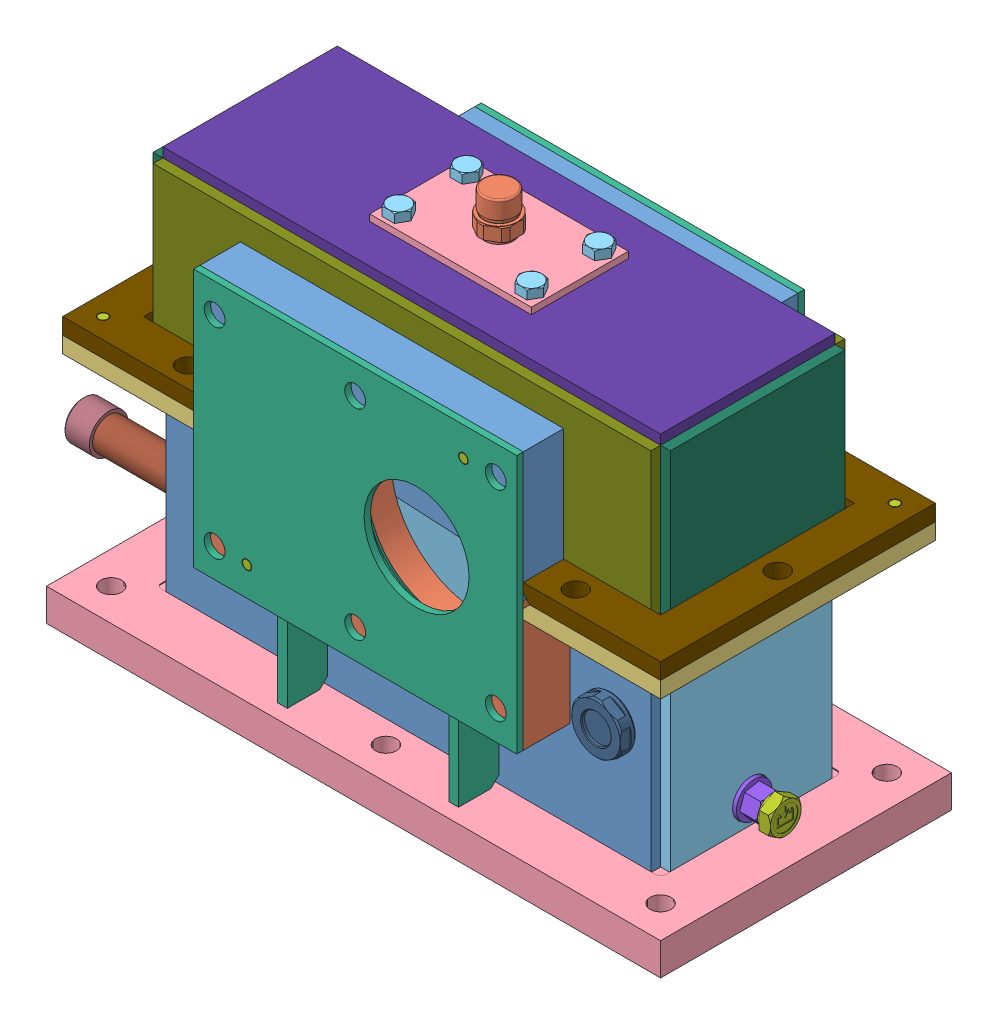
SolidWorks assembly kuciste_bez_poklopca, configuration Default. Lengths in mm.
Overall size (410 284 180).
61 component instances, 25 part files, 19 mates.
Components (placement in the parent):
- DONJE_KUCISTE-1: DONJE_KUCISTE [zajedno obrađeno] at (117.7992 130.0596 336.2434) size (410 154.5 180)
  - glavni_lim-1: glavni_lim [rupa za staklo] at (0 84.5 50) x (1 0 0) z (0 -1 0) size (300 6 130)
  - kockavratila-1: kockavratila [probusena_s_rupama_prednja] at (0 114.5 50) x (1 0 0) z (0 -1 0) size (200 35 80)
  - prirubnica_donja-1: prirubnica_donja [urezana_s_rupama] at (-100 144.5 0) size (85 10 170)
  - temeljna_ploca-1: temeljna_ploca [Default] at origin size (380 20 180)
  - bocni_lim-2: bocni_lim [cijevni registar] at (-150 84.5 0) x (0 0 -1) z (0 1 0) size (100 6 130)
  - glavni_lim-2: glavni_lim [Default] at (0 84.5 -56) x (1 0 0) z (0 -1 0) size (300 6 130)
  - kockavratila-2: kockavratila [probusena_s_rupama_zadnja] at (0 114.5 -50) x (-1 0 0) z (0 -1 0) size (200 35 80)
  - prirubnica_donja-2: prirubnica_donja [urezana_s_rupama] at (100 144.5 0) x (-1 0 0) z (0 0 -1) size (85 10 170)
  - bocni_lim-3: bocni_lim [irezan_ispust] at (156 84.5 0) x (0 0 1) z (0 -1 0) size (100 6 130)
  - rebro-1: rebro [Default] at (-50 47.25 68.5) x (0 -1 0) z (0 0 -1) size (54.5 6 25)
  - rebro-2: rebro [Default] at (50 47.25 68.5) x (0 1 0) z (0 0 -1) size (54.5 6 25)
  - rebro-3: rebro [Default] at (56 47.25 -68.5) x (0 1 0) z (0 0 1) size (54.5 6 25)
  - rebro-4: rebro [Default] at (-50 47.25 -68.5) x (0 1 0) z (0 0 1) size (54.5 6 25)
  - Oil fill plugs TCD.10x1.5-1: Oil fill plugs TCD.10x1.5 [Default] at (161.5 34.5 0) size (16 24.13 19)
  - Hexagon nut DIN 6331-M10-1: Hexagon nut DIN 6331-M10 [Default] at (154 34.5 0) x (0 -0.652064 0.758164) z (0 0.758164 0.652064) size (22 15 22)
  - Brass nut GH.M26x1.5-NK-1: Brass nut GH.M26x1.5-NK [Default] at (125 88.5 50) x (0 0 1) z (-0.706547 -0.707666 0) size (3.5 33 30)
  - Oil level sight glass GN 743-18-M26x1_5-A-1: Oil level sight glass GN 743-18-M26x1_5-A [Default] at (125 88.5 48) x (1 0 0) z (0 -1 0) size (32 17 32)
  - Prirubnica_c.reg._sklop-1: Prirubnica_c.reg._sklop [Default] at (-142.8722 78.3632 -24.5463) x (0 0.999301 0.037387) z (0 -0.037387 0.999301) size (33.22 66 33.22)
    - prirubnica_cijevnog_registra-1: prirubnica_cijevnog_registra [Default] at (-7.5365 11.1278 62.3717) size (20 50 20)
    - Gasket DIN 7603-AL-8-11_5-A(semering registra)-1: Gasket DIN 7603-AL-8-11_5-A(semering registra) [Default] at (-7.5365 26.6278 62.3717) x (0 -1 0) z (0.887885 0 0.460066) size (1 11.4 11.4)
    - Gasket DIN 7603-AL-8-11_5-A(semering registra)-2: Gasket DIN 7603-AL-8-11_5-A(semering registra) [Default] at (-7.5365 28.6278 62.3717) x (0 -1 0) z (-0.546944 0 0.837169) size (1 11.4 11.4)
    - Gasket DIN 7603-AL-8-11_5-A(semering registra)-3: Gasket DIN 7603-AL-8-11_5-A(semering registra) [Default] at (-7.5365 29.6278 62.3717) x (0 1 0) z (-0.564882 0 -0.825172) size (1 11.4 11.4)
    - Gasket DIN 7603-AL-8-11_5-A(semering registra)-4: Gasket DIN 7603-AL-8-11_5-A(semering registra) [Default] at (-7.5365 30.6278 62.3717) x (0 1 0) z (-0.564882 0 -0.825172) size (1 11.4 11.4)
    - Gasket DIN 7603-AL-8-11_5-A(semering registra)-5: Gasket DIN 7603-AL-8-11_5-A(semering registra) [Default] at (-7.5365 27.6278 62.3717) x (0 -1 0) z (-0.546944 0 0.837169) size (1 11.4 11.4)
    - M16x30-1: M16x30 [Default] at (-7.5365 77.1278 62.3717) x (0 -1 0) z (-0.546944 0 0.837169) size (46 24 24)
  - Prirubnica_c.reg._sklop-2: Prirubnica_c.reg._sklop [Default] at (-142.8722 84.718 -98.196) x (0 0.990097 0.140386) z (0 -0.140386 0.990097) size (33.22 66 33.22)
    - prirubnica_cijevnog_registra-1: prirubnica_cijevnog_registra [Default] at (-7.5365 11.1278 62.3717) size (20 50 20)
    - Gasket DIN 7603-AL-8-11_5-A(semering registra)-1: Gasket DIN 7603-AL-8-11_5-A(semering registra) [Default] at (-7.5365 26.6278 62.3717) x (0 -1 0) z (0.887885 0 0.460066) size (1 11.4 11.4)
    - Gasket DIN 7603-AL-8-11_5-A(semering registra)-2: Gasket DIN 7603-AL-8-11_5-A(semering registra) [Default] at (-7.5365 28.6278 62.3717) x (0 -1 0) z (-0.546944 0 0.837169) size (1 11.4 11.4)
    - Gasket DIN 7603-AL-8-11_5-A(semering registra)-3: Gasket DIN 7603-AL-8-11_5-A(semering registra) [Default] at (-7.5365 29.6278 62.3717) x (0 1 0) z (-0.564882 0 -0.825172) size (1 11.4 11.4)
    - Gasket DIN 7603-AL-8-11_5-A(semering registra)-4: Gasket DIN 7603-AL-8-11_5-A(semering registra) [Default] at (-7.5365 30.6278 62.3717) x (0 1 0) z (-0.564882 0 -0.825172) size (1 11.4 11.4)
    - Gasket DIN 7603-AL-8-11_5-A(semering registra)-5: Gasket DIN 7603-AL-8-11_5-A(semering registra) [Default] at (-7.5365 27.6278 62.3717) x (0 -1 0) z (-0.546944 0 0.837169) size (1 11.4 11.4)
    - M16x30-1: M16x30 [Default] at (-7.5365 77.1278 62.3717) x (0 -1 0) z (-0.546944 0 0.837169) size (46 24 24)
  - unutarnji lim-1: unutarnji lim [Default] at (-1.7035 28.2254 0) x (0.99863 -0.052336 0) z (0 0 -1) size (296.96 17.98 100)
- GORNJE KUČIŠTE-1: GORNJE KUČIŠTE [zajednicki obrađena] at (84.6226 294.5596 336.2434) x (-1 0 0) z (0 0 1) size (370 129.5 170)
  - gornji bočni lim veći-1: gornji bočni lim veći [Default] at (-187.1766 -40 0) x (0 1 0) z (0 0 1) size (90 6 108)
  - gornji glavni lim-1: gornji glavni lim [Default] at (27.434 -40 -60) x (-1 0 0) z (0 1 0) size (308 6 90)
  - gornji_gornji lim ravni-1: gornji_gornji lim ravni [Default] at (-33.1766 -91 0) size (308 6 108)
  - prirubnica_gornja-1: prirubnica_gornja [prirubnica s rupama ] at origin size (85 10 170)
  - gornji bočni lim veći-2: gornji bočni lim veći [Default] at (126.8234 -40 0) x (0 1 0) z (0 0 1) size (90 6 108)
  - gornji glavni lim-2: gornji glavni lim [Default] at (-93.7872 -40 60) x (1 0 0) z (0 1 0) size (308 6 90)
  - prirubnica_gornja-2: prirubnica_gornja [prirubnica s rupama ] at (-66.3532 0 0) x (-1 0 0) z (0 0 -1) size (85 10 170)
  - gornja kocka vratila-1: gornja kocka vratila [prednja_probusena_s_rupama] at (-33.1766 -30 50) x (-1 0 0) z (0 1 0) size (200 35 80)
  - gornja kocka vratila-2: gornja kocka vratila [zadnja_probusena_s_rupama] at (-33.1766 -30 -50) x (1 0 0) z (0 1 0) size (200 35 80)
  - poklopac sa odzračnikom-1: poklopac sa odzračnikom [Default] at (-34.3484 -81.4985 -29.5408) x (-1 0 0) z (0 0 1) size (100 33 60)
    - Breather valve GN 881-M12x1_5-200-MS-M-1: Breather valve GN 881-M12x1_5-200-MS-M [Default] at (-1.1718 13.5015 29.5408) size (23 33 23.5)
    - Mounting nut GN 7430-M12x1_5-MS-1: Mounting nut GN 7430-M12x1_5-MS [Default] at (-1.1718 6.5015 29.5408) x (1 0 0) z (0 -1 0) size (16 17.5 3)
    - poklopac-1: poklopac [Default] at (-1.1718 9.5015 29.5408) size (100 4 60)
  - DIN933 M8x14mm-1: DIN933 M8x14mm [Default] at (-74.1766 -100.68 21) x (0 1 0) z (0 0 1) size (19.69 15.02 15.02)
  - DIN933 M8x14mm-2: DIN933 M8x14mm [Default] at (7.8234 -100.68 21) x (0 1 0) z (0 0 1) size (19.69 15.02 15.02)
  - DIN933 M8x14mm-3: DIN933 M8x14mm [Default] at (7.8234 -100.68 -21) x (0 1 0) z (0 0 1) size (19.69 15.02 15.02)
  - DIN933 M8x14mm-4: DIN933 M8x14mm [Default] at (-74.1766 -100.68 -21) x (0 1 0) z (0 0 1) size (19.69 15.02 15.02)
- poklopac_vratila-1: poklopac_vratila [zajedno_obrađen_prednji] at (117.7992 284.5596 425.2434) x (1 0 0) z (0 1 0) size (200 17.13 160)
- poklopac_vratila-2: poklopac_vratila [zajedno_obrađen] at (117.7992 284.5596 247.2434) x (1 0 0) z (0 -1 0) size (200 17.13 160)
- parallel pin hardened_din-1: parallel pin hardened_din [DIN EN 28734 - 6 x 14 - A - St] at (290.2992 280.5596 263.7434) x (0 1 0) z (0 0 1) size (14 6 6)
- parallel pin hardened_din-2: parallel pin hardened_din [DIN EN 28734 - 6 x 14 - A - St] at (184.7992 346.5596 411.2434) x (0 0 1) z (0 -1 0) size (14 6 6)
- parallel pin hardened_din-3: parallel pin hardened_din [DIN EN 28734 - 6 x 14 - A - St] at (50.7992 222.5596 411.2434) x (0 0 1) z (-1 0 0) size (14 6 6)
- parallel pin hardened_din-4: parallel pin hardened_din [DIN EN 28734 - 6 x 14 - A - St] at (50.7992 222.5596 247.2434) x (0 0 1) z (-1 0 0) size (14 6 6)
- parallel pin hardened_din-5: parallel pin hardened_din [DIN EN 28734 - 6 x 14 - A - St] at (-54.7008 280.5596 408.7434) x (0 1 0) z (0 0 1) size (14 6 6)
- parallel pin hardened_din-6: parallel pin hardened_din [DIN EN 28734 - 6 x 14 - A - St] at (184.7992 346.5596 247.2434) x (0 0 1) z (-1 0 0) size (14 6 6)
Mates (geometry in assembly coordinates):
- Coincident1: coincident anti-aligned: plane of DONJE_KUCISTE-1/prirubnica_donja-2 through (217.7992 284.5596 336.2434) normal (0 1 0); plane of GORNJE KUČIŠTE-1/prirubnica_gornja-2 through (150.9758 284.5596 336.2434) normal (0 -1 0)
- Coincident2: coincident aligned: plane of DONJE_KUCISTE-1/kockavratila-1 through (117.7992 244.5596 421.2434) normal (0 0 1); plane of GORNJE KUČIŠTE-1/gornja kocka vratila-1 through (117.7992 324.5596 421.2434) normal (0 0 1)
- Coincident3: coincident aligned: plane of DONJE_KUCISTE-1/prirubnica_donja-2 through (302.7992 284.5596 251.2434) normal (1 0 0); plane of GORNJE KUČIŠTE-1/prirubnica_gornja-1 through (302.7992 284.5596 251.2434) normal (1 0 0)
- Coincident4: coincident anti-aligned: plane of GORNJE KUČIŠTE-1/gornja kocka vratila-1 through (117.7992 324.5596 421.2434) normal (0 0 1); plane of poklopac_vratila-1 through (117.7992 284.5596 421.2434) normal (0 0 -1)
- Coincident6: coincident anti-aligned: plane of GORNJE KUČIŠTE-1/gornja kocka vratila-2 through (117.7992 324.5596 251.2434) normal (0 0 -1); plane of poklopac_vratila-2 through (117.7992 284.5596 251.2434) normal (0 0 1)
- Concentric3: concentric anti-aligned: cylinder of DONJE_KUCISTE-1/kockavratila-1 through (155.7992 284.5596 230.6799) axis (0 0 1) radius 55; circle of poklopac_vratila-1
- Concentric4: concentric anti-aligned: cylinder of DONJE_KUCISTE-1/kockavratila-2 through (55.7992 284.5596 441.8068) axis (0 0 -1) radius 31; cylinder of poklopac_vratila-2 through (55.7992 284.5596 247.2434) axis (0 0 1) radius 17.5
- Concentric5: concentric anti-aligned: circle of GORNJE KUČIŠTE-1/prirubnica_gornja-2; circle of parallel pin hardened_din-5
- Coincident8: coincident aligned: plane of GORNJE KUČIŠTE-1/prirubnica_gornja-2 through (150.9758 294.5596 336.2434) normal (0 1 0); plane of parallel pin hardened_din-5 through (-54.7008 294.5596 408.7434) normal (0 1 0)
- Coincident9: coincident aligned: plane of poklopac_vratila-1 through (117.7992 284.5596 425.2434) normal (0 0 1); plane of parallel pin hardened_din-3 through (50.7992 222.5596 425.2434) normal (0 0 1)
- Concentric7: concentric anti-aligned: circle of poklopac_vratila-1; circle of parallel pin hardened_din-3
- Concentric8: concentric anti-aligned: circle of poklopac_vratila-1; circle of parallel pin hardened_din-2
- Coincident11: coincident aligned: plane of poklopac_vratila-1 through (117.7992 284.5596 425.2434) normal (0 0 1); plane of parallel pin hardened_din-2 through (184.7992 346.5596 425.2434) normal (0 0 1)
- Concentric9: concentric anti-aligned: circle of poklopac_vratila-2; circle of parallel pin hardened_din-6
- Coincident12: coincident aligned: plane of poklopac_vratila-2 through (117.7992 284.5596 247.2434) normal (0 0 -1); plane of parallel pin hardened_din-6 through (184.7992 349.2381 247.2434) normal (0 0 -1)
- Concentric10: concentric anti-aligned: circle of poklopac_vratila-2; circle of parallel pin hardened_din-4
- Coincident13: coincident aligned: plane of poklopac_vratila-2 through (117.7992 284.5596 247.2434) normal (0 0 -1); plane of parallel pin hardened_din-4 through (50.7992 225.2381 247.2434) normal (0 0 -1)
- Concentric11: concentric anti-aligned: cylinder of GORNJE KUČIŠTE-1/prirubnica_gornja-1 through (290.2992 284.5596 263.7434) axis (0 1 0) radius 3; circle of parallel pin hardened_din-1
- Coincident14: coincident aligned: plane of GORNJE KUČIŠTE-1/prirubnica_gornja-1 through (84.6226 294.5596 336.2434) normal (0 1 0); plane of parallel pin hardened_din-1 through (290.2992 294.5596 263.7434) normal (0 1 0)
